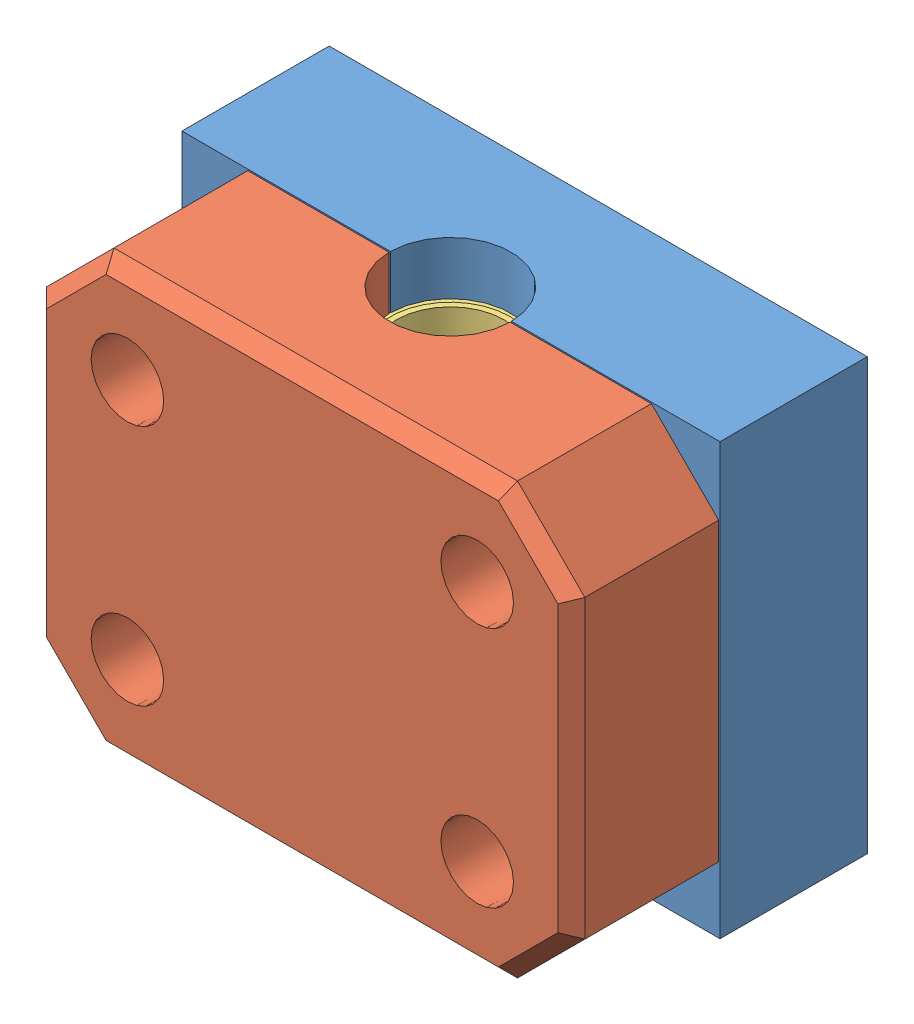
SolidWorks assembly Rudder Carriage Linear Bearing Holder, configuration Default. Lengths in mm.
Overall size (123.48 58.99 94.03).
11 component instances, 5 part files, 20 mates.
Components (placement in the parent):
- Rudder Carriage Linear Bearing Holder Lower Shell-1: Rudder Carriage Linear Bearing Holder Lower Shell [Default] at origin size (40 32 10.95)
- Rudder Carriage Linear Bearing Holder Upper Shell-1: Rudder Carriage Linear Bearing Holder Upper Shell [Default] at origin size (123.48 58.99 77.75)
- LM8UU v2-1: LM8UU v2 [Default] at (-339.725 6533.262 2827.3504) size (14.96 23.84 14.96)
- 93625A200 - NUT, M5-0.8, NYLOC, 18-8-1: 93625A200 - NUT, M5-0.8, NYLOC, 18-8 [93625A200] at (-326.725 6524.262 2838.3504) x (-1 0 0) z (0 1 0) size (8 5.15 9.24)
- 93705A838 - SHCS, M5-0.8 x 30mm, SELF-LOCKING, 18-8-1: 93705A838 - SHCS, M5-0.8 x 30mm, SELF-LOCKING, 18-8 [91292A194] at (-326.725 6524.262 2846.3504) x (0.267759 0.963486 0) z (0 0 1) size (8.5 8.5 35.49)
- 93625A200 - NUT, M5-0.8, NYLOC, 18-8-2: 93625A200 - NUT, M5-0.8, NYLOC, 18-8 [93625A200] at (-352.725 6524.262 2838.3504) x (-1 0 0) z (0 1 0) size (8 5.15 9.24)
- 93705A838 - SHCS, M5-0.8 x 30mm, SELF-LOCKING, 18-8-2: 93705A838 - SHCS, M5-0.8 x 30mm, SELF-LOCKING, 18-8 [91292A194] at (-352.725 6524.262 2846.3504) x (0.111609 0.993752 0) z (0 0 1) size (8.5 8.5 35.49)
- 93625A200 - NUT, M5-0.8, NYLOC, 18-8-3: 93625A200 - NUT, M5-0.8, NYLOC, 18-8 [93625A200] at (-326.725 6542.262 2838.3504) x (-1 0 0) z (0 1 0) size (8 5.15 9.24)
- 93705A838 - SHCS, M5-0.8 x 30mm, SELF-LOCKING, 18-8-3: 93705A838 - SHCS, M5-0.8 x 30mm, SELF-LOCKING, 18-8 [91292A194] at (-326.725 6542.262 2846.3504) x (-0.015836 0.999875 0) z (0 0 1) size (8.5 8.5 35.49)
- 93625A200 - NUT, M5-0.8, NYLOC, 18-8-4: 93625A200 - NUT, M5-0.8, NYLOC, 18-8 [93625A200] at (-352.725 6542.262 2838.3504) x (-1 0 0) z (0 1 0) size (8 5.15 9.24)
- 93705A838 - SHCS, M5-0.8 x 30mm, SELF-LOCKING, 18-8-4: 93705A838 - SHCS, M5-0.8 x 30mm, SELF-LOCKING, 18-8 [91292A194] at (-352.725 6542.262 2846.3504) x (-0.108968 0.994045 0) z (0 0 1) size (8.5 8.5 35.49)
Mates (geometry in assembly coordinates):
- Concentric133: concentric aligned: cylinder of Rudder Carriage Linear Bearing Holder Upper Shell-1 through (-326.725 6524.262 2827.3504) axis (0 0 -1) radius 2.7; circle of 93625A200 - NUT, M5-0.8, NYLOC, 18-8-1
- Coincident481: coincident anti-aligned: plane of Rudder Carriage Linear Bearing Holder Upper Shell-1 through (-339.725 6533.262 2838.3504) normal (0 0 1); plane of 93625A200 - NUT, M5-0.8, NYLOC, 18-8-1 through (-326.725 6519.6432 2838.3504) normal (0 0 -1)
- Parallel6: parallel anti-aligned: plane of Rudder Carriage Linear Bearing Holder Upper Shell-1 through (-332.2812 6598.4907 0) normal (1 0 0); plane of 93625A200 - NUT, M5-0.8, NYLOC, 18-8-1 through (-330.725 6526.5714 2843.3504) normal (-1 0 0)
- Concentric134: concentric anti-aligned: cylinder of Rudder Carriage Linear Bearing Holder Lower Shell-1 through (-326.725 6524.262 2827.3504) axis (0 0 -1) radius 2.7; cylinder of 93705A838 - SHCS, M5-0.8 x 30mm, SELF-LOCKING, 18-8-1 through (-326.725 6524.262 2811.3504) axis (0 0 1) radius 4.25
- Coincident483: coincident anti-aligned: plane of Rudder Carriage Linear Bearing Holder Lower Shell-1 through (-339.725 6533.262 2816.3504) normal (0 0 -1); plane of 93705A838 - SHCS, M5-0.8 x 30mm, SELF-LOCKING, 18-8-1 through (-326.725 6524.262 2816.3504) normal (0 0 1)
- Parallel7: parallel anti-aligned: plane of Rudder Carriage Linear Bearing Holder Upper Shell-1 through (-332.2812 6598.4907 0) normal (1 0 0); plane of 93625A200 - NUT, M5-0.8, NYLOC, 18-8-2 through (-356.725 6526.5714 2843.3504) normal (-1 0 0)
- Coincident484: coincident anti-aligned: plane of Rudder Carriage Linear Bearing Holder Upper Shell-1 through (-339.725 6533.262 2838.3504) normal (0 0 1); plane of 93625A200 - NUT, M5-0.8, NYLOC, 18-8-2 through (-352.725 6519.6432 2838.3504) normal (0 0 -1)
- Concentric135: concentric aligned: cylinder of Rudder Carriage Linear Bearing Holder Upper Shell-1 through (-352.725 6524.262 2827.3504) axis (0 0 -1) radius 2.7; circle of 93625A200 - NUT, M5-0.8, NYLOC, 18-8-2
- Coincident485: coincident anti-aligned: plane of Rudder Carriage Linear Bearing Holder Lower Shell-1 through (-339.725 6533.262 2816.3504) normal (0 0 -1); plane of 93705A838 - SHCS, M5-0.8 x 30mm, SELF-LOCKING, 18-8-2 through (-352.725 6524.262 2816.3504) normal (0 0 1)
- Concentric136: concentric anti-aligned: cylinder of Rudder Carriage Linear Bearing Holder Upper Shell-1 through (-352.725 6524.262 2827.3504) axis (0 0 -1) radius 2.7; cylinder of 93705A838 - SHCS, M5-0.8 x 30mm, SELF-LOCKING, 18-8-2 through (-352.725 6524.262 2811.3504) axis (0 0 1) radius 4.25
- Coincident486: coincident anti-aligned: plane of Rudder Carriage Linear Bearing Holder Upper Shell-1 through (-339.725 6533.262 2838.3504) normal (0 0 1); plane of 93625A200 - NUT, M5-0.8, NYLOC, 18-8-3 through (-326.725 6537.6432 2838.3504) normal (0 0 -1)
- Parallel8: parallel anti-aligned: plane of Rudder Carriage Linear Bearing Holder Upper Shell-1 through (-332.2812 6598.4907 0) normal (1 0 0); plane of 93625A200 - NUT, M5-0.8, NYLOC, 18-8-3 through (-330.725 6544.5714 2843.3504) normal (-1 0 0)
- Concentric137: concentric aligned: cylinder of Rudder Carriage Linear Bearing Holder Upper Shell-1 through (-326.725 6542.262 2827.3504) axis (0 0 -1) radius 2.7; circle of 93625A200 - NUT, M5-0.8, NYLOC, 18-8-3
- Coincident487: coincident anti-aligned: plane of Rudder Carriage Linear Bearing Holder Lower Shell-1 through (-339.725 6533.262 2816.3504) normal (0 0 -1); plane of 93705A838 - SHCS, M5-0.8 x 30mm, SELF-LOCKING, 18-8-3 through (-326.725 6542.262 2816.3504) normal (0 0 1)
- Concentric138: concentric anti-aligned: cylinder of Rudder Carriage Linear Bearing Holder Upper Shell-1 through (-326.725 6542.262 2827.3504) axis (0 0 -1) radius 2.7; cylinder of 93705A838 - SHCS, M5-0.8 x 30mm, SELF-LOCKING, 18-8-3 through (-326.725 6542.262 2811.3504) axis (0 0 1) radius 4.25
- Coincident488: coincident anti-aligned: plane of Rudder Carriage Linear Bearing Holder Upper Shell-1 through (-339.725 6533.262 2838.3504) normal (0 0 1); plane of 93625A200 - NUT, M5-0.8, NYLOC, 18-8-4 through (-352.725 6537.6432 2838.3504) normal (0 0 -1)
- Parallel9: parallel anti-aligned: plane of Rudder Carriage Linear Bearing Holder Upper Shell-1 through (-332.2812 6598.4907 0) normal (1 0 0); plane of 93625A200 - NUT, M5-0.8, NYLOC, 18-8-4 through (-356.725 6544.5714 2843.3504) normal (-1 0 0)
- Concentric139: concentric aligned: cylinder of Rudder Carriage Linear Bearing Holder Upper Shell-1 through (-352.725 6542.262 2827.3504) axis (0 0 -1) radius 2.7; circle of 93625A200 - NUT, M5-0.8, NYLOC, 18-8-4
- Coincident489: coincident anti-aligned: plane of Rudder Carriage Linear Bearing Holder Lower Shell-1 through (-339.725 6533.262 2816.3504) normal (0 0 -1); plane of 93705A838 - SHCS, M5-0.8 x 30mm, SELF-LOCKING, 18-8-4 through (-352.725 6542.262 2816.3504) normal (0 0 1)
- Concentric140: concentric anti-aligned: cylinder of Rudder Carriage Linear Bearing Holder Upper Shell-1 through (-352.725 6542.262 2827.3504) axis (0 0 -1) radius 2.7; cylinder of 93705A838 - SHCS, M5-0.8 x 30mm, SELF-LOCKING, 18-8-4 through (-352.725 6542.262 2811.3504) axis (0 0 1) radius 4.25
